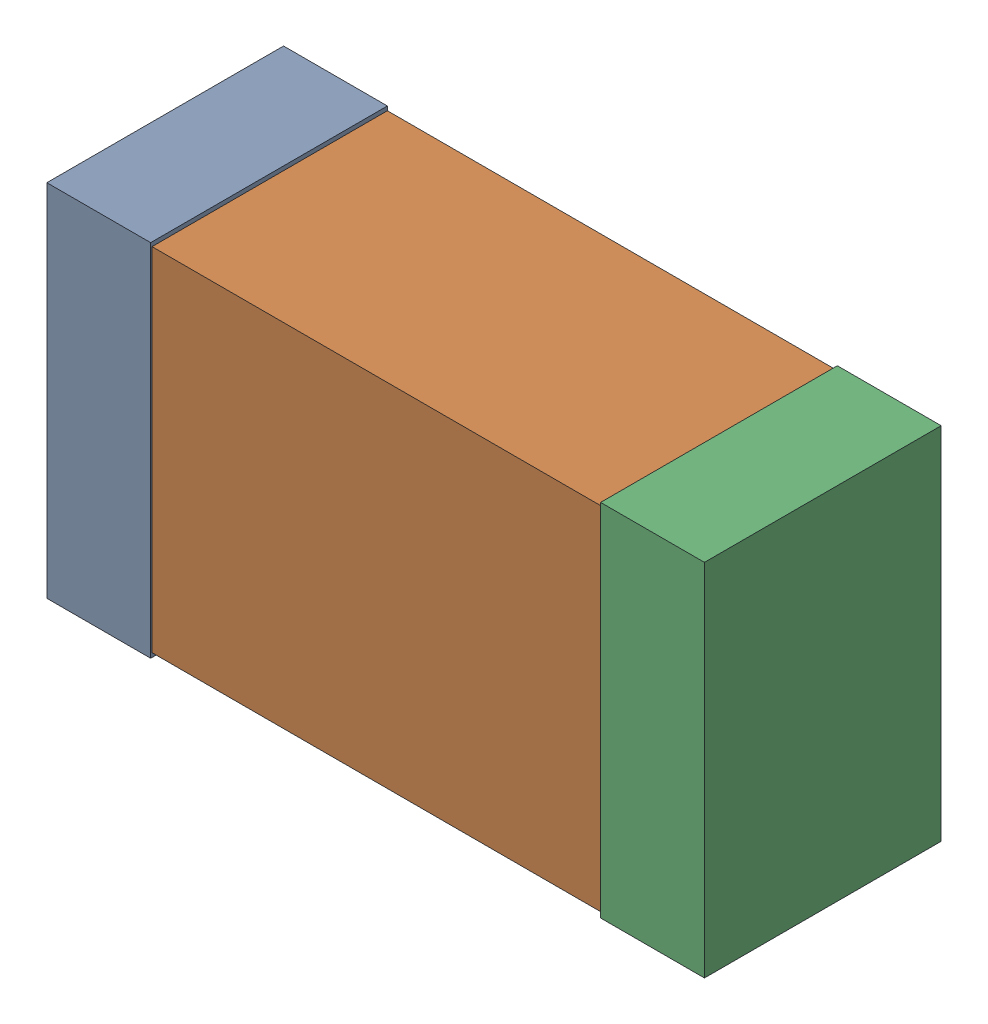
SolidWorks assembly USB67_C9, configuration Default. Lengths in mm.
Overall size (2.38 1.3 0.85).
6 component instances, 2 part files, 0 mates.
Components (placement in the parent):
- 384311232-1: 384311232 [Default] at (137.371 89.281 0) size (0.38 1.3 0.85)
  - Extruded_8-1: Extruded_8 [Default] at origin size (0.38 1.3 0.85)
- 402662800-1: 402662800 [Default] at (138.371 89.281 0) size (2.2 1.27 0.85)
  - Extruded_30-1: Extruded_30 [Default] at origin size (2.2 1.27 0.85)
- 384311232-2: 384311232 [Default] at (139.371 89.281 0) size (0.38 1.3 0.85)
  - Extruded_8-1: Extruded_8 [Default] at origin size (0.38 1.3 0.85)
